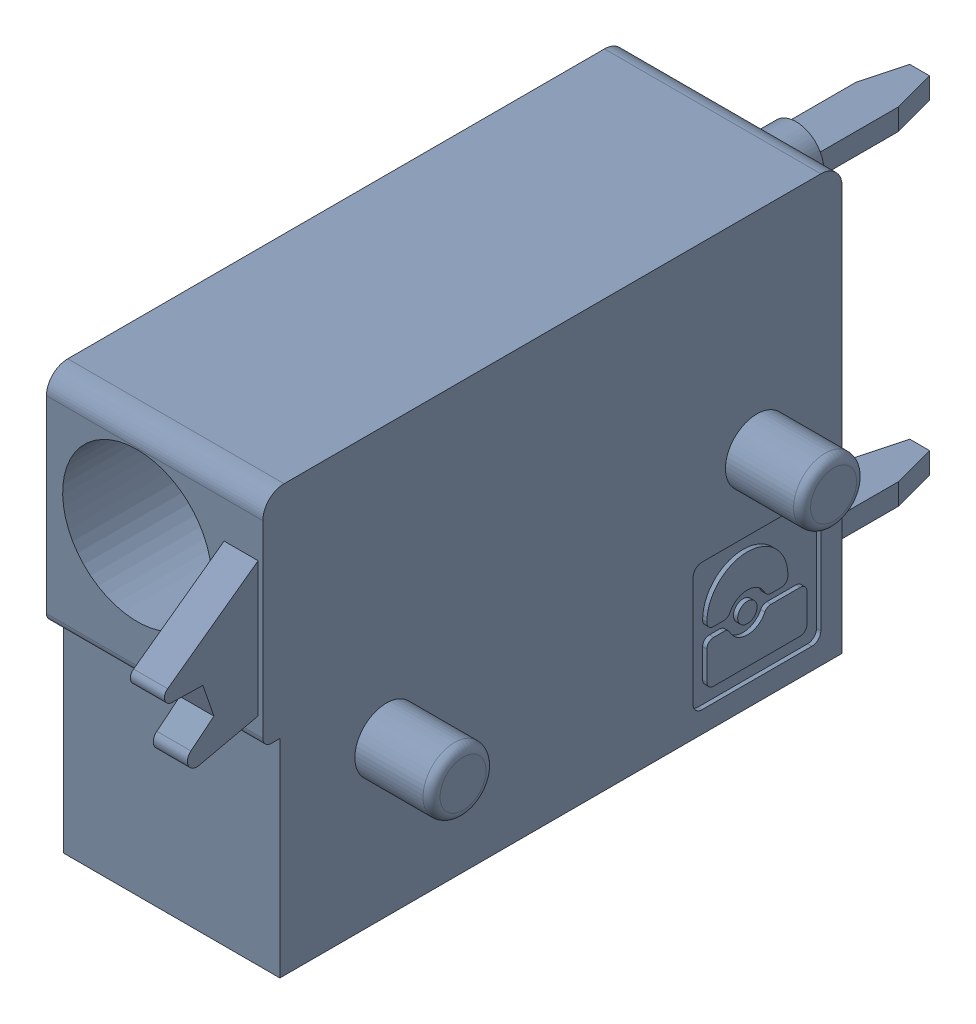
SolidWorks assembly J7, configuration Default. Lengths in mm.
Overall size (6.88 10 19.2).
2 component instances, 1 part files, 0 mates.
Components (placement in the parent):
- 1790348-1: 1790348 [Default] at (14.6051 -7.6199 0) x (0 1 0) z (1 0 0) size (10 19.2 6.88)
  - ffkds-v2-5.08-1: ffkds-v2-5.08 [Default] at (-23.7414 -38.158 -2.54) x (0 -1 0) z (0 0 1) size (19.2 10 6.88)
